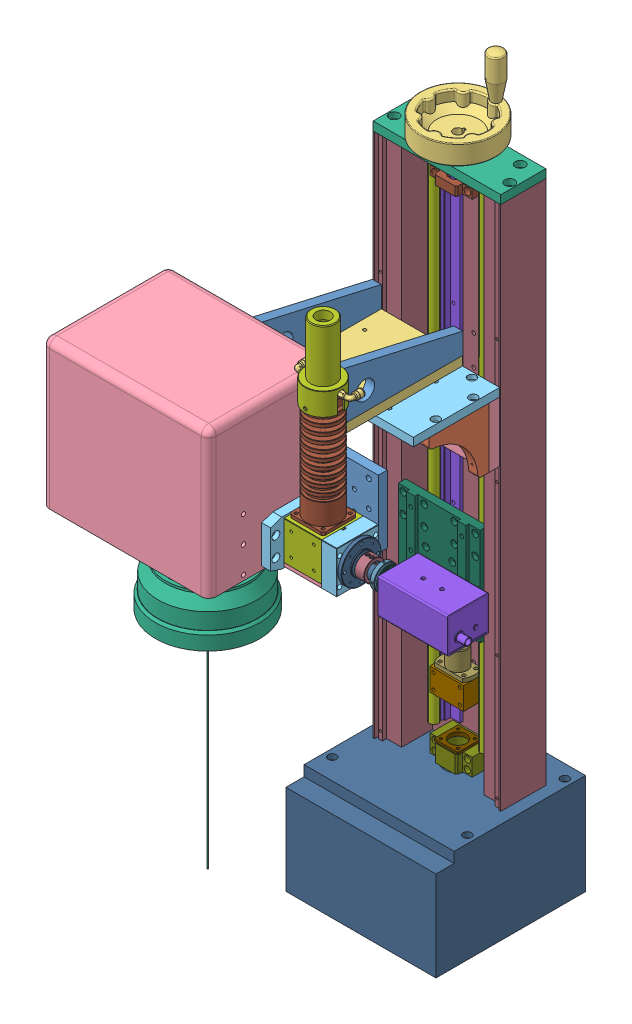
SolidWorks assembly 振镜焊接工作台, configuration 默认. Lengths in mm.
Overall size (490.7 1012.5 545.05).
103 component instances, 64 part files, 3 mates.
Components (placement in the parent):
- ZJHJGZT_ASM_1_ASM-1: ZJHJGZT_ASM_1_ASM [默认] at origin size (295 1012.5 371)
  - 3_01_01001_1GH_GF_ASM_1_ASM-1: 3_01_01001_1GH_GF_ASM_1_ASM [默认] at (542.5 -2.2 -189.5) x (0 0 1) z (-1 0 0)
  - 3_01_01001_1GH_GF_ASM_1_ASM-2: 3_01_01001_1GH_GF_ASM_1_ASM [默认] at (-35.5 -2.2 -302.5) x (-1 0 0) z (0 0 -1)
  - 3_01_01001_1GH_GF_ASM_1_ASM-3: 3_01_01001_1GH_GF_ASM_1_ASM [默认] at (-557.5 -2.2 189.5) x (0 0 1) z (-1 0 0)
  - TRE_GH_GF_ASM_1_ASM-1: TRE_GH_GF_ASM_1_ASM [默认] at (340 312.85 315) x (0 -1 0) z (1 0 0)
  - OXL---_GH_GF_ASM_1_ASM-1: OXL---_GH_GF_ASM_1_ASM [默认] at (375 720 357) x (1 0 0) z (0 -1 0)
    - XL-CT_FSD_GH_GF_ASM_1_ASM-1: XL-CT_FSD_GH_GF_ASM_1_ASM [默认] at (2.0942 1 0.9985)
    - HG350-00_FSD_GH_GF_ASM_1_ASM-2: HG350-00_FSD_GH_GF_ASM_1_ASM [默认] at (-173.75 -145 1) x (0 -1 0) z (0 0 1)
  - HOUMEN_QL-_QW_DY_GG_GH_GF_1_ASM-1: HOUMEN_QL-_QW_DY_GG_GH_GF_1_ASM [默认] at (60 285 -375) x (1 0 0) z (0 -1 0)
  - 3_01_01001_1GH_GF_ASM_1_ASM-4: 3_01_01001_1GH_GF_ASM_1_ASM [默认] at (542.5 -2.2 189.5) x (0 0 1) z (-1 0 0)
  - 3_01_01001_1GH_GF_ASM_1_ASM-5: 3_01_01001_1GH_GF_ASM_1_ASM [默认] at (-557.5 -2.2 -189.5) x (0 0 -1) z (1 0 0)
  - DYLISED_ASM_1_ASM-1: DYLISED_ASM_1_ASM [默认] at (-225 590 0) x (-1 0 0) z (0 0 -1) size (295 1012.5 371)
    - LIANGJIEBAN-02_GG_1_1-1: LIANGJIEBAN-02_GG_1_1 [默认] at (140 508.9453 -30) size (280 90 12)
    - SHENGJIAN-0201_GG_ASM_1_ASM-1: SHENGJIAN-0201_GG_ASM_1_ASM [默认] at (90 -751.3898 82.5) size (200 1012.5 214)
      - PRODUCT_294513_FDH_GG_ASM_1_ASM-1: PRODUCT_294513_FDH_GG_ASM_1_ASM [默认] at (105 726 214.5) x (0 0 -1) z (1 0 0) size (214 1012.5 200)
        - ______1-288995_FDH_GG_1-1: ______1-288995_FDH_GG_1 [默认] at (75 478.3351 79) x (0 -1 0) z (0 0 -1) size (80 80 12)
        - PRODUCT_159491_FDH_GG_1-1: PRODUCT_159491_FDH_GG_1 [默认] at (32 74 0) x (0 -1 0) z (0.632108 0 0.77488)
        - PRODUCT_159996_FDH_GG_1-1: PRODUCT_159996_FDH_GG_1 [默认] at (32 710 0) x (0.236507 0 -0.97163) z (0.97163 0 0.236507) size (100 96.5 102.25)
        - _________DEFAULT-289233_FDH_GG_-1: _________DEFAULT-289233_FDH_GG_ [默认] at (75 438.3351 0.25) x (0 0 -1) z (0 1 0) size (169.5 14 80)
        - PRODUCT_161183_FDH_GG_1-1: PRODUCT_161183_FDH_GG_1 [默认] at (176 489.3351 0.25) x (0 0 -1) z (1 0 0) size (169.5 11 115)
        - ______1-288995_FDH_GG_1-2: ______1-288995_FDH_GG_1 [默认] at (75 478.3351 -78.5) x (0 -1 0) z (0 0 -1) size (80 80 12)
        - PRODUCT_160704_FDH_GG_1-1: PRODUCT_160704_FDH_GG_1 [默认] at (32 700 0) x (0 0 -1) z (1 0 0) size (170 11.5 60)
        - PRODUCT_160501_FDH_GG_ASM_1_ASM-1: PRODUCT_160501_FDH_GG_ASM_1_ASM [默认] at (30.002 530 34) x (0 0 -1) z (0 -1 0) size (40 25 650)
          - ____2-74989_FDH_GG_1-1: ____2-74989_FDH_GG_1 [默认] at origin size (12 12 650)
          - ____3-75054_FDH_GG_1-1: ____3-75054_FDH_GG_1 [默认] at origin size (40 13.9 650)
        - PRODUCT_159736_FDH_GG_1-1: PRODUCT_159736_FDH_GG_1 [默认] at (32 107.5123 0) x (0 0 1) z (0 -1 0) size (45 32 30)
        - PRODUCT_295573_FDH_GG_1-1: PRODUCT_295573_FDH_GG_1 [默认] at (57 -14 0) x (0 0 1) z (-1 0 0) size (200 134 199.27)
        - PRODUCT_160157_FDH_GG_1-1: PRODUCT_160157_FDH_GG_1 [默认] at (32 674 0) x (0 0 1) z (0 1 0) size (56 38 12)
        - _________DEFAULT-289268_FDH_GG_-1: _________DEFAULT-289268_FDH_GG_ [默认] at (32 107.5123 0) x (1 0 0) z (0 1 0) size (25 45 30.31)
        - PRODUCT_294687_FDH_GG_1-1: PRODUCT_294687_FDH_GG_1 [默认] at origin size (60 700 170)
        - PRODUCT_160927_FDH_GG_1-1: PRODUCT_160927_FDH_GG_1 [默认] at (32 -67 0) x (0 0 -1) z (-1 0 0) size (79 53 79)
        - PRODUCT_159238_FDH_GG_1-1: PRODUCT_159238_FDH_GG_1 [默认] at (47 307.51 0) x (0 0 -1) z (0 -1 0) size (109 14 130)
        - ______1-289080_FDH_GG_1-1: ______1-289080_FDH_GG_1 [默认] at (32 12.9991 0.0002) x (0 -0.00004 1) z (0 1 0.00004) size (56 38 23)
        - PRODUCT_295488_FDH_GG_1-1: PRODUCT_295488_FDH_GG_1 [默认] at (47 -67 0) x (-1 0 0) z (0 -1 0) size (79 79 159)
        - PRODUCT_160501_FDH_GG_ASM_1_ASM-2: PRODUCT_160501_FDH_GG_ASM_1_ASM [默认] at (30.002 530 -34) x (0 0 -1) z (0 -1 0) size (40 25 650)
          - ____2-74989_FDH_GG_1-1: ____2-74989_FDH_GG_1 [默认] at origin size (12 12 650)
          - ____3-75054_FDH_GG_1-1: ____3-75054_FDH_GG_1 [默认] at origin size (40 13.9 650)
        - PRODUCT_295177_FDH_GG_1-1: PRODUCT_295177_FDH_GG_1 [默认] at (32 27.4991 0.0008) x (-1 0 0) z (0 -1 -0.00004) size (32 32 5)
    - JIAQIANGJI01_QL-_QW_DY_GG_1-1: JIAQIANGJI01_QL-_QW_DY_GG_1 [默认] at (274 475.9453 106) size (12 78 260)
    - JIAQIANGJI01_QL-_QW_DY_GG_1-2: JIAQIANGJI01_QL-_QW_DY_GG_1 [默认] at (166 475.9453 106.4563) size (12 78 260)
    - CCDGUDINGBAN_GG_1-1: CCDGUDINGBAN_GG_1 [默认] at (70 508.9453 -18) x (-1 0 0) z (0 0 1) size (90 56 12)
    - LIANJIEBAN1_QL-_QW_DY_GG_1_1-1: LIANJIEBAN1_QL-_QW_DY_GG_1_1 [默认] at (220 463.9453 106) size (120 12 260)
- 振镜头-2: 振镜头 [默认] at (-252.5 709.234 138) x (0 0 -1) z (1 0 0) size (174.05 674.5 475.7)
  - 170-550__ASM-1: 170-550__ASM [默认] at (169.8767 309 283.6276) x (-1 0 0) z (0 -1 0)
  - 7_QL-_QW_DY_GG-1: 7_QL-_QW_DY_GG [默认] at (18 442.2113 -141.5) x (0 0 1) z (0 -1 0) size (222 168 197.12)
  - CCDGUDINGBAN_GG-1: CCDGUDINGBAN_GG [默认] at (37.5 386.7113 -12.5) x (-1 0 0) z (0 0 1) size (90 60 12)
  - 170CJ-1: 170CJ [默认] at (-2.55 344.7113 -95.33) size (139 373 139)
  - L-DEVLI-SANRE-D_ASM-1: L-DEVLI-SANRE-D_ASM [默认] at (37.5 389.2113 19) x (0 0 -1) z (0 1 0) size (247.2 56 287.5)
    - ZHONGXINKUANGJIA_L-1: ZHONGXINKUANGJIA_L [默认] at origin size (51 56 51)
    - 54X38X5-DS_L_ASM-1: 54X38X5-DS_L_ASM [默认] at (-4.4497 0 -7.4497) x (0.707107 0 -0.707107) z (0 -1 0) size (58 7 42)
      - BABIANYAGAI_L-1: BABIANYAGAI_L [默认] at origin size (58 6.5 42)
      - 54X38DIANPIAN_L-1: 54X38DIANPIAN_L [默认] at (0 1 0) size (54 1 38)
      - 54X38X2BAJIAO_L-1: 54X38X2BAJIAO_L [默认] at (0 2 0) size (54 5 38)
    - KUOSUJING-DS_L_ASM-1: KUOSUJING-DS_L_ASM [默认] at (0.5 0 23) x (0 -1 0) z (-1 0 0) size (46 151 46)
      - CD36F150AW_L-1: CD36F150AW_L [默认] at origin size (46 150 46)
      - CD36_L-1: CD36_L [默认] at (0 10.5 0) x (-1 0 0) z (0 0 1) size (36 6 36)
      - SET-COLLAR_L-1: SET-COLLAR_L [默认] at (0 3 0) size (37 1.5 37)
      - PRESSING-RING_L-1: PRESSING-RING_L [默认] at (0 3 0) x (-1 0 0) z (0 0 1) size (40 4 40)
    - FOCIS-DS_L_ASM-1: FOCIS-DS_L_ASM [默认] at (0.5 0 173) x (-1 0 0) z (0 1 0) size (80.9 14.75 30.75)
      - FOCIS-01_L-1: FOCIS-01_L [默认] at origin size (44 12 12)
      - 10_L-1: 10_L [默认] at (0 5 0) size (9.94 4.21 9.94)
      - FOCIS-SSET01_L-1: FOCIS-SSET01_L [默认] at (0 5 0) x (-1 0 0) z (0 0 1) size (10 4 10)
      - FOCIS-SET_L-1: FOCIS-SET_L [默认] at (0 1 0) x (-1 0 0) z (0 0 1) size (12 5 12)
      - 0XINGQUAN25_L-1: 0XINGQUAN25_L [默认] at (0 0.33 0) size (29.5 2 29.5)
      - O-14_L-1: O-14_L [默认] at (0 0.33 0) size (17.56 1.78 17.56)
      - LJIETOU_L-1: LJIETOU_L [默认] at (17.5 6 0) x (0 -1 0) z (1 0 0) size (9.5 20 22.95)
      - LJIETOU_L-2: LJIETOU_L [默认] at (-17.5 6 0) x (0 1 0) z (-1 0 0) size (9.5 20 22.95)
    - Z-YAGAI_L-1: Z-YAGAI_L [默认] at (0 0 -28) x (0 0 1) z (1 0 0) size (5 56 51)
    - DIANLUZUO_L_ASM-1: DIANLUZUO_L_ASM [默认] at (-45.5 0 -2.5) x (0 0 1) z (0 1 0) size (56 20 56)
      - DIANQIGUDINGZUO_L-1: DIANQIGUDINGZUO_L [默认] at origin size (56 20 56)
      - HB468_L-1: HB468_L [默认] at (0 12 0) x (-1 0 0) z (0 0 1) size (10 6 10)
      - 12YAQUAN_L-1: 12YAQUAN_L [默认] at (0 6 0) x (-1 0 0) z (0 0 1) size (12 5 12)
      - PC-_L_ASM-1: PC-_L_ASM [默认] at (0 6.5 0) size (36 10.5 36)
        - PC-01_FG_L-1: PC-01_FG_L [默认] at origin size (36 1.5 36)
        - PC-D_FG_L-1: PC-D_FG_L [默认] at (13 1.5 -6) size (6 10.5 6)
        - PC-D_FG_L-2: PC-D_FG_L [默认] at (13.435 1.5 4.9497) x (0.707107 0 0.707107) z (-0.707107 0 0.707107) size (6 10.5 6)
        - PC-D_FG_L-3: PC-D_FG_L [默认] at (6 1.5 13) x (0 0 1) z (-1 0 0) size (6 10.5 6)
        - PC-D_FG_L-4: PC-D_FG_L [默认] at (-4.9497 1.5 13.435) x (-0.707107 0 0.707107) z (-0.707107 0 -0.707107) size (6 10.5 6)
        - PC-D_FG_L-5: PC-D_FG_L [默认] at (-13 1.5 6) x (-1 0 0) z (0 0 -1) size (6 10.5 6)
        - PC-D_FG_L-6: PC-D_FG_L [默认] at (-13.435 1.5 -4.9497) x (-0.707107 0 -0.707107) z (0.707107 0 -0.707107) size (6 10.5 6)
        - PC-D_FG_L-7: PC-D_FG_L [默认] at (-6 1.5 -13) x (0 0 -1) z (1 0 0) size (6 10.5 6)
        - PC-D_FG_L-8: PC-D_FG_L [默认] at (4.9497 1.5 -13.435) x (0.707107 0 -0.707107) z (0.707107 0 0.707107) size (6 10.5 6)
    - WEITIANKUAI_L_ASM-1: WEITIANKUAI_L_ASM [默认] at (-50.5 0 -2.5) x (0 -1 0) z (0 0 1) size (53 53.5 53)
      - CD18_L-1: CD18_L [默认] at origin size (53 36 53)
      - XIANWEIKUAI_L-1: XIANWEIKUAI_L [默认] at (0 -5 0) x (0 0 -1) z (-1 0 0) size (15.5 40 15.5)
      - DANGKUAI_L-1: DANGKUAI_L [默认] at (0 -11 7) x (0 -1 0) z (-1 0 0) size (13 2.79 5)
      - DANGKUAI_L-2: DANGKUAI_L [默认] at (0 -11 -7) x (0 -1 0) z (1 0 0) size (13 2.79 5)
      - M28_L-1: M28_L [默认] at (0 -4.5 0) x (0 0 1) z (1 0 0) size (28 13 28)
      - M28WAIQUAN_L-1: M28WAIQUAN_L [默认] at (0 -14.5 0) x (-1 0 0) z (0 0 1)
      - QIANDANGKUAI_L-1: QIANDANGKUAI_L [默认] at (0 -30 0) size (32 6 32)
      - DINGQUAN_L-1: DINGQUAN_L [默认] at (0 -41 0) size (30.03 12 30.03)
      - 18JINGPIAN_L-1: 18JINGPIAN_L [默认] at (0 -2 0) size (18 2.5 18)
      - 18GEQUAN_L-1: 18GEQUAN_L [默认] at (0 -0.5 0) size (18 1 18)
      - M20YAQUAN_L-1: M20YAQUAN_L [默认] at (0 1 0) size (20 4 20)
      - 30OXINGQUAN_L-1: 30OXINGQUAN_L [默认] at (0 4.75 0) x (-1 0 0) z (0 0 -1) size (37.7 3.5 37.7)
    - JU-BAO-DS_L_ASM-1: JU-BAO-DS_L_ASM [默认] at (25.5 0 -2.5) x (0 -1 0) z (0 0 1) size (46 19 46)
      - 07_SS_LEN_BG_L-1: 07_SS_LEN_BG_L [默认] at origin size (46 17 46)
      - 36JINGPIAN_LEN_BG_L-1: 36JINGPIAN_LEN_BG_L [默认] at origin size (36 4 36)
      - 08_SS_LEN_BG_L-1: 08_SS_LEN_BG_L [默认] at (0 9.5 0) x (-1 0 0) z (0 0 1) size (36 5.5 36)
      - 09_SS_LEN_BG_L-1: 09_SS_LEN_BG_L [默认] at (0 3.5 0) x (-1 0 0) z (0 0 1) size (40 4 40)
      - 10_SS_LEN_BG_L-1: 10_SS_LEN_BG_L [默认] at (0 17.5 0) x (-1 0 0) z (0 0 1) size (44 9 44)
    - BAOHUTAO_L-1: BAOHUTAO_L [默认] at (0.5 0 157) x (-1 0 0) z (0 1 0) size (48 100 48)
    - CCD-1: CCD [默认] at (-192.5 0 -2.5) x (0 -1 0) z (0 0 1) size (55 108.2 47)
Mates (geometry in assembly coordinates):
- 重合2: coincident anti-aligned: plane of ZJHJGZT_ASM_1_ASM-1/DYLISED_ASM_1_ASM-1/LIANGJIEBAN-02_GG_1_1-1 through (-365 1098.9453 36) normal (0 0 1); plane of 振镜头-2/7_QL-_QW_DY_GG-1 through (-505 1248.9453 36) normal (0 0 -1)
- 重合3: coincident aligned: plane of ZJHJGZT_ASM_1_ASM-1/DYLISED_ASM_1_ASM-1/LIANGJIEBAN-02_GG_1_1-1 through (-505 1053.9453 36) normal (-1 0 0); plane of 振镜头-2/7_QL-_QW_DY_GG-1 through (-505 1248.9453 204) normal (-1 0 0)
- 重合4: coincident aligned: plane of ZJHJGZT_ASM_1_ASM-1/DYLISED_ASM_1_ASM-1/LIANJIEBAN1_QL-_QW_DY_GG_1_1-1 through (-445 1053.9453 -106) normal (0 -1 0); plane of 振镜头-2/7_QL-_QW_DY_GG-1 through (-394 1053.9453 120) normal (0 -1 0)
